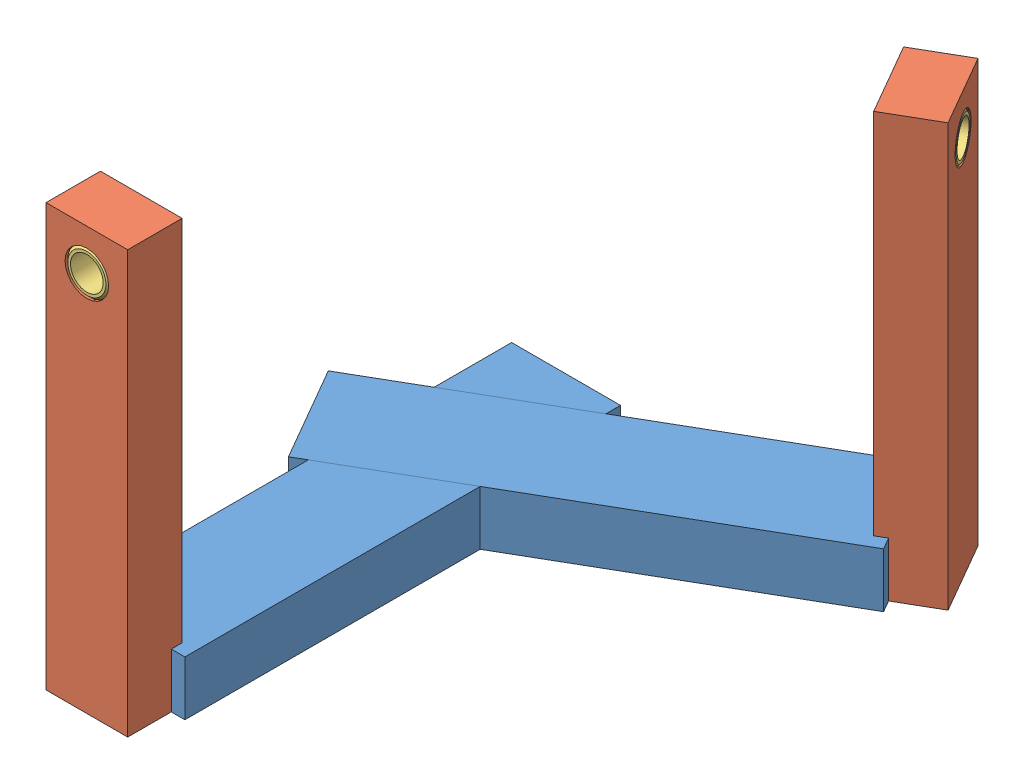
SolidWorks assembly 1, configuration 預設. Lengths in mm.
Overall size (84.96 77.5 108.5).
6 component instances, 3 part files, 13 mates.
Components (placement in the parent):
- 110303047-01-2: 110303047-01 [預設] at (36.0711 38.4239 59.0686) x (0 0 -1) z (0 1 0) size (80 20 10)
- 110303047-01-3: 110303047-01 [預設] at (53.3916 48.4239 29.0686) x (-0.866025 0 0.5) z (0 -1 0) size (80 20 10)
- 110303047-02-1: 110303047-02 [預設] at (36.0711 77.1739 97.0686) size (15 77.5 10)
- 110303047-02-2: 110303047-02 [預設] at (86.3006 77.1739 10.0686) x (-0.5 0 -0.866025) z (0.866025 0 -0.5) size (15 77.5 10)
- 110303047-12-1: 110303047-12 [預設] at (36.0711 108.4239 107.0686) size (8 8 10)
- 110303047-12-2: 110303047-12 [預設] at (94.9609 108.4239 5.0686) x (-0.5 0 -0.866025) z (0.866025 0 -0.5) size (8 8 10)
Mates (geometry in assembly coordinates):
- 重合/共線/共點1: coincident: plane of 110303047-01-2 through (26.0711 43.4239 56.3891) normal (-0.5 0 -0.866025); plane of 110303047-01-3 through (93.0327 38.4239 17.7288) normal (0.5 0 0.866025)
- 重合/共線/共點2: coincident: plane of 110303047-01-2 through (26.0711 48.4239 99.0686) normal (-1 0 0); plane of 110303047-01-3 through (26.0711 43.4239 33.2951) normal (1 0 0)
- 重合/共線/共點3: coincident anti-aligned: plane of 110303047-01-2 through (36.0711 43.4239 59.0686) normal (0 1 0); plane of 110303047-01-3 through (53.3916 43.4239 29.0686) normal (0 -1 0)
- 重合/共線/共點4: coincident: plane of 110303047-01-2 through (28.5711 48.4239 97.0686) normal (0 0 1); plane of 110303047-02-1 through (36.0711 77.1739 97.0686) normal (0 0 -1)
- 重合/共線/共點5: coincident: plane of 110303047-01-2 through (36.0711 38.4239 59.0686) normal (0 -1 0); plane of 110303047-02-1 through (28.5711 38.4239 107.0686) normal (0 -1 0)
- 重合/共線/共點6: coincident anti-aligned: plane of 110303047-01-2 through (43.5711 48.4239 97.0686) normal (-1 0 0); plane of 110303047-02-1 through (43.5711 38.4239 107.0686) normal (1 0 0)
- 重合/共線/共點7: coincident: point of assembly; line of assembly; moEndPointRef_w of 110303047-01-3; line of 110303047-02-2 through (90.0506 115.9239 16.5638) axis (0 -1 0)
- 重合/共線/共點8: coincident: plane of 110303047-01-3 through (82.5506 38.4239 3.5734) normal (0.866025 0 -0.5); plane of 110303047-02-2 through (86.3006 77.1739 10.0686) normal (-0.866025 0 0.5)
- 重合/共線/共點9: coincident aligned: plane of 110303047-01-3 through (53.3916 38.4239 29.0686) normal (0 -1 0); plane of 110303047-02-2 through (98.7109 38.4239 11.5638) normal (0 -1 0)
- 同軸心1: concentric: cylinder of 110303047-02-1 through (36.0711 108.4239 107.0686) axis (0 0 -1) radius 4; cylinder of 110303047-12-1 through (36.0711 108.4239 116.5055) axis (0 0 1) radius 4
- 同軸心2: concentric: cylinder of 110303047-02-2 through (94.9609 108.4239 5.0686) axis (-0.866025 0 0.5) radius 4; cylinder of 110303047-12-2 through (103.1335 108.4239 0.3501) axis (0.866025 0 -0.5) radius 4
- 重合/共線/共點10: coincident aligned: plane of 110303047-02-2 through (94.9609 77.1739 5.0686) normal (0.866025 0 -0.5); plane of 110303047-12-2 through (94.9609 111.9239 5.0686) normal (0.866025 0 -0.5)
- 重合/共線/共點11: coincident aligned: plane of 110303047-02-1 through (36.0711 77.1739 107.0686) normal (0 0 1); plane of 110303047-12-1 through (36.0711 111.9239 107.0686) normal (0 0 1)
